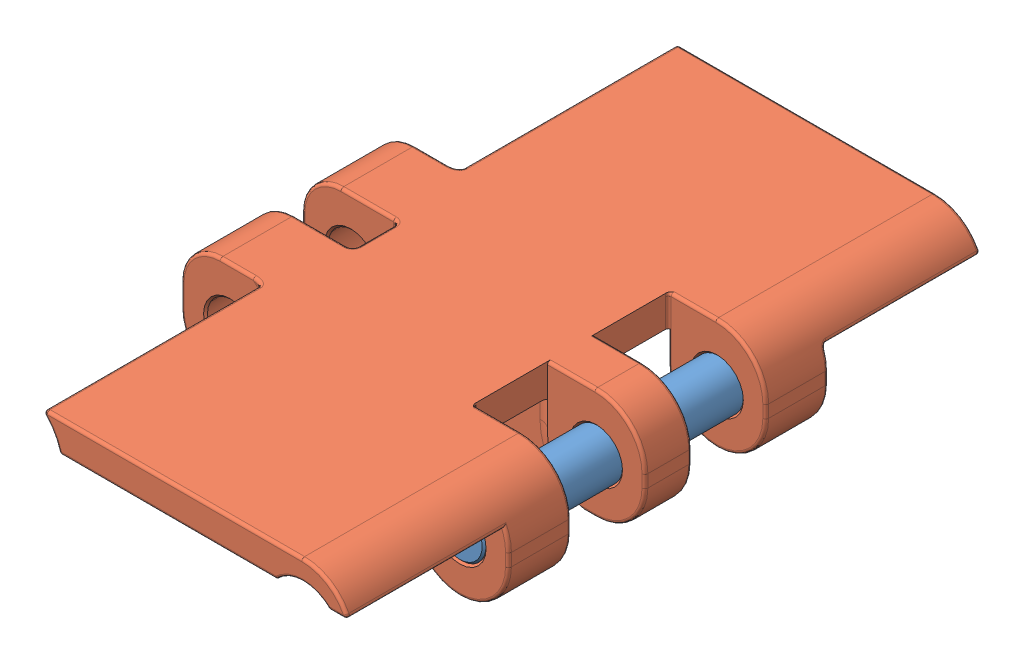
SolidWorks assembly Rexnord-820-AS 820 K-3-14, configuration Default. Lengths in mm.
Overall size (50.8 15.22 82.55).
2 component instances, 2 part files, 0 mates.
Components (placement in the parent):
- Rexnord-820-AS 820 K-3-14_Pin-1: Rexnord-820-AS 820 K-3-14_Pin [Default] at origin size (6.35 6.35 41.66)
- Rexnord-820-AS 820 K-3-14_8201(AS)-1: Rexnord-820-AS 820 K-3-14_8201(AS) [Default] at (-19.05 0.127 0) size (50.8 15.22 82.55)
